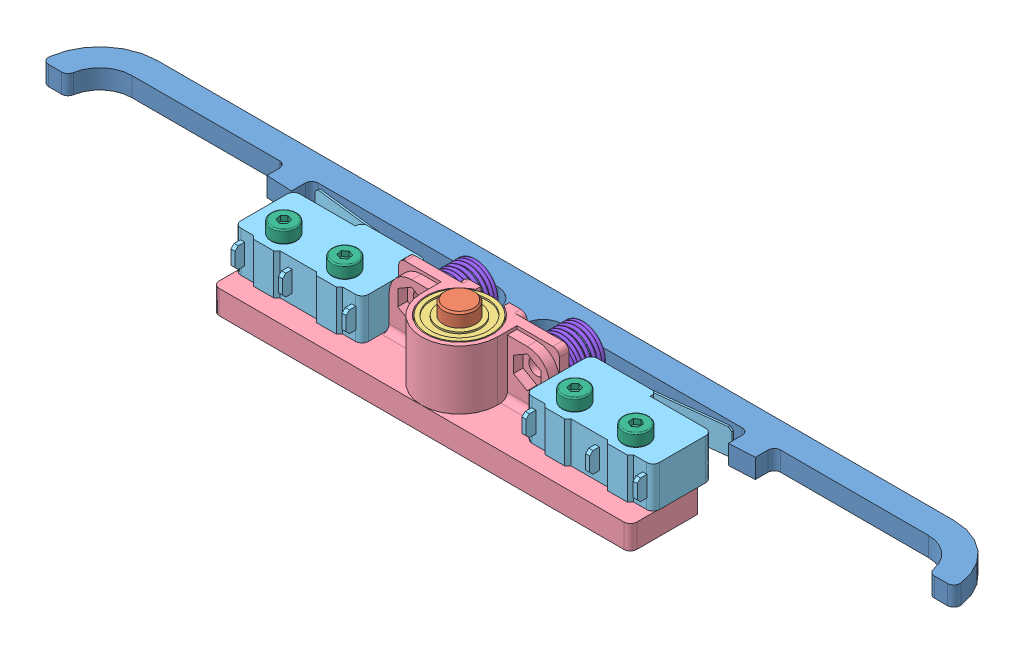
SolidWorks assembly bumper, configuration Default. Lengths in mm.
Overall size (141.87 14.98 21.84).
17 component instances, 8 part files, 45 mates.
Components (placement in the parent):
- bumper-body-1: bumper-body [Default] at (0 5.7 -13) size (141.87 3 19.5)
- bumper-pin-1: bumper-pin [Default] at (0 -1.5 0) x (0.989126 0 0.147073) z (-0.147073 0 0.989126) size (4.98 14.98 4.98)
- bearing-5x10x4-1: bearing-5x10x4 [Default] at (0 7.4 0) x (0.98772 0 -0.156233) z (0.156233 0 0.98772) size (10 4 10)
- bearing-5x10x4-3: bearing-5x10x4 [Default] x (0.862962 0 -0.505269) z (0.505269 0 0.862962) size (10 4 10)
- bumper-mount-1: bumper-mount [Default] at origin size (65 12.9 11.45)
- bumper-switch-1: bumper-switch [Default] at (22.65 5.375 -2.4) size (19.85 6.35 14.2)
- cap-screw-m2-10mm-1: cap-screw-m2-10mm [Default] at (27.4 10.55 -0.05) x (0 -1 0) z (0.048273 0 0.998834) size (12 4 4)
- nut-m2-1: nut-m2 [Default] at (27.4 -1.5 -0.05) x (-0.866025 0 0.5) z (0 1 0) size (4.62 4 2)
- cap-screw-m2-10mm-2: cap-screw-m2-10mm [Default] at (17.9 10.55 -0.05) x (0 -1 0) z (0.235644 0 0.97184) size (12 4 4)
- nut-m2-2: nut-m2 [Default] at (17.9 -1.5 -0.05) x (-0.866025 0 0.5) z (0 1 0) size (4.62 4 2)
- bumper-switch-3: bumper-switch [Default] at (-22.65 5.375 -2.4) x (-1 0 0) z (0 0 1) size (19.85 6.35 14.2)
- cap-screw-m2-10mm-6: cap-screw-m2-10mm [Default] at (-27.4 10.55 -0.05) x (0 -1 0) z (0.942478 0 0.334268) size (12 4 4)
- cap-screw-m2-10mm-8: cap-screw-m2-10mm [Default] at (-17.9 10.55 -0.05) x (0 -1 0) z (0.942478 0 0.334268) size (12 4 4)
- nut-m2-6: nut-m2 [Default] at (-17.9 -1.5 -0.05) x (-0.866025 0 0.5) z (0 1 0) size (4.62 4 2)
- nut-m2-8: nut-m2 [Default] at (-27.4 -1.5 -0.05) x (-0.866025 0 0.5) z (0 1 0) size (4.62 4 2)
- bumper-spring-1: bumper-spring [Default] at (-8.365 5.7 -11) x (1 0 0) z (0 -1 0) size (7.25 5.46 7.25)
- bumper-spring-2: bumper-spring [Default] at (8.365 5.7 -11) x (0.987351 0.158553 0) z (0.158553 -0.987351 0) size (7.25 5.46 7.25)
Mates (geometry in assembly coordinates):
- Concentric1: concentric: cylinder of bumper-body-1 through (0 7.2 0) axis (0 -1 0) radius 2.5; cylinder of bumper-pin-1 through (0 13.48 0) axis (0 -1 0) radius 2.49
- Concentric2: concentric: cylinder of bumper-pin-1 through (0 13.48 0) axis (0 -1 0) radius 2.49; cylinder of bearing-5x10x4-1 through (0 11.4 0) axis (0 -1 0) radius 2.5
- Concentric4: concentric: cylinder of bumper-pin-1 through (0 13.48 0) axis (0 -1 0) radius 2.49; cylinder of bearing-5x10x4-3 through (0 4 0) axis (0 -1 0) radius 2.5
- Concentric7: concentric: cylinder of bumper-pin-1 through (0 13.88 0) axis (0 -1 0) radius 2.49; cylinder of ? through (0 10 0) axis (0 -1 0) radius 2.525
- Coincident3: coincident: plane of bumper-body-1 through (-0.0163 8.5 -12) normal (0 1 0); plane of ? through (0 8.5 0) normal (0 -1 0)
- Coincident4: coincident: plane of bearing-5x10x4-1 through (0 10 0) normal (0 -1 0); plane of ? through (0 10 0) normal (0 1 0)
- Concentric8: concentric: cylinder of bumper-pin-1 through (0 13.88 0) axis (0 -1 0) radius 2.49; cylinder of ? through (0 4 0) axis (0 1 0) radius 2.525
- Coincident5: coincident: plane of bumper-body-1 through (-0.0163 5.5 -12) normal (0 -1 0); plane of ? through (0 5.5 0) normal (0 1 0)
- Coincident6: coincident: plane of bearing-5x10x4-3 through (0 4 0) normal (0 1 0); plane of ? through (0 4 0) normal (0 -1 0)
- Coincident8: coincident: plane of bearing-5x10x4-3 through (0 0 0) normal (0 -1 0); plane of bumper-mount-1 through (0 0 0) normal (0 1 0)
- Concentric10: concentric: cylinder of bearing-5x10x4-3 through (0 4 0) axis (0 -1 0) radius 5; cylinder of bumper-mount-1 through (0 11.4 0) axis (0 -1 0) radius 5.2
- Distance1: distance = 0.2 mm: plane of bumper-body-1 through (0 4.2 -13) normal (0 -1 0); plane of bearing-5x10x4-3 through (0 4 0) normal (0 1 0)
- Distance2: distance = 0.2 mm: plane of bumper-body-1 through (0 7.2 -13) normal (0 1 0); plane of bearing-5x10x4-1 through (0 7.4 0) normal (0 -1 0)
- Coincident13: coincident: plane of bumper-pin-1 through (0 -1.5 0) normal (0 -1 0); plane of bumper-mount-1 through (0 -1.5 0) normal (0 -1 0)
- Parallel1: parallel: plane of bumper-body-1 through (0 7.2 -15) normal (0 0 -1); plane of bumper-mount-1 through (0 11.4 -4.55) normal (0 0 -1)
- Concentric11: concentric: line of bumper-mount-1 through (17.9 2.2 -0.05) axis (0 1 0); cylinder of bumper-switch-1 through (17.9 8.55 -0.05) axis (0 -1 0) radius 1.25
- Concentric12: concentric: line of bumper-mount-1 through (27.4 2.2 -0.05) axis (0 1 0); cylinder of bumper-switch-1 through (27.4 8.55 -0.05) axis (0 -1 0) radius 1.25
- Coincident15: coincident: plane of bumper-mount-1 through (0 2.2 0) normal (0 1 0); plane of bumper-switch-1 through (22.65 2.2 -2.4) normal (0 -1 0)
- Concentric13: concentric: cylinder of bumper-switch-1 through (27.4 8.55 -0.05) axis (0 -1 0) radius 1.25; cylinder of cap-screw-m2-10mm-1 through (27.4 12.8318 -0.05) axis (0 1 0) radius 1
- Coincident16: coincident: plane of bumper-switch-1 through (22.65 8.55 -2.4) normal (0 1 0); plane of cap-screw-m2-10mm-1 through (28.3988 8.55 -0.0983) normal (0 -1 0)
- Concentric14: concentric: cylinder of cap-screw-m2-10mm-1 through (27.4 12.8318 -0.05) axis (0 1 0) radius 1; cylinder of nut-m2-1 through (27.4 0.5 -0.05) axis (0 -1 0) radius 1
- Coincident17: coincident: plane of bumper-mount-1 through (0 0.5 0) normal (0 -1 0); plane of nut-m2-1 through (27.4 0.5 -0.05) normal (0 1 0)
- Parallel2: parallel: plane of bumper-mount-1 through (25.25 0.5 0) normal (1 0 0); plane of nut-m2-1 through (25.4 0.5 -1.2047) normal (-1 0 0)
- Concentric15: concentric: cylinder of bumper-switch-1 through (17.9 8.55 -0.05) axis (0 -1 0) radius 1.25; cylinder of cap-screw-m2-10mm-2 through (17.9 12.8318 -0.05) axis (0 1 0) radius 1
- Coincident19: coincident: plane of bumper-switch-1 through (22.65 8.55 -2.4) normal (0 1 0); plane of cap-screw-m2-10mm-2 through (18.8718 8.55 -0.2856) normal (0 -1 0)
- Concentric16: concentric: cylinder of cap-screw-m2-10mm-2 through (17.9 12.8318 -0.05) axis (0 1 0) radius 1; cylinder of nut-m2-2 through (17.9 0.5 -0.05) axis (0 -1 0) radius 1
- Coincident21: coincident: plane of bumper-mount-1 through (0 0.5 0) normal (0 -1 0); plane of nut-m2-2 through (17.9 0.5 -0.05) normal (0 1 0)
- Parallel3: parallel: plane of bumper-mount-1 through (15.75 0.5 0) normal (1 0 0); plane of nut-m2-2 through (15.9 0.5 -1.2047) normal (-1 0 0)
- Concentric21: concentric: line of bumper-mount-1 through (-27.4 2.2 -0.05) axis (0 1 0); cylinder of bumper-switch-3 through (-27.4 2.2 -0.05) axis (0 1 0) radius 1.25
- Concentric22: concentric: line of bumper-mount-1 through (-17.9 2.2 -0.05) axis (0 1 0); cylinder of bumper-switch-3 through (-17.9 2.2 -0.05) axis (0 1 0) radius 1.25
- Coincident25: coincident: plane of bumper-mount-1 through (0 2.2 0) normal (0 1 0); plane of bumper-switch-3 through (-22.65 2.2 -2.4) normal (0 -1 0)
- Concentric23: concentric: cylinder of bumper-switch-3 through (-27.4 2.2 -0.05) axis (0 1 0) radius 1.25; cylinder of cap-screw-m2-10mm-6 through (-27.4 12.8318 -0.05) axis (0 1 0) radius 1
- Coincident26: coincident: plane of bumper-switch-3 through (-22.65 8.55 -2.4) normal (0 1 0); plane of cap-screw-m2-10mm-6 through (-27.0657 8.55 -0.9925) normal (0 -1 0)
- Concentric24: concentric: cylinder of bumper-switch-3 through (-17.9 2.2 -0.05) axis (0 1 0) radius 1.25; cylinder of cap-screw-m2-10mm-8 through (-17.9 12.8318 -0.05) axis (0 1 0) radius 1
- Coincident27: coincident: plane of bumper-switch-3 through (-22.65 8.55 -2.4) normal (0 1 0); plane of cap-screw-m2-10mm-8 through (-17.5657 8.55 -0.9925) normal (0 -1 0)
- Concentric25: concentric: cylinder of cap-screw-m2-10mm-8 through (-17.9 12.8318 -0.05) axis (0 1 0) radius 1; cylinder of nut-m2-6 through (-17.9 0.5 -0.05) axis (0 -1 0) radius 1
- Coincident28: coincident: plane of bumper-mount-1 through (0 0.5 0) normal (0 -1 0); plane of nut-m2-6 through (-17.9 0.5 -0.05) normal (0 1 0)
- Parallel4: parallel: plane of bumper-mount-1 through (-20.05 0.5 0) normal (1 0 0); plane of nut-m2-6 through (-19.9 0.5 -1.2047) normal (-1 0 0)
- Concentric26: concentric: cylinder of cap-screw-m2-10mm-6 through (-27.4 12.8318 -0.05) axis (0 1 0) radius 1; cylinder of nut-m2-8 through (-27.4 0.5 -0.05) axis (0 -1 0) radius 1
- Coincident29: coincident: plane of bumper-mount-1 through (0 0.5 0) normal (0 -1 0); plane of nut-m2-8 through (-27.4 0.5 -0.05) normal (0 1 0)
- Parallel5: parallel: plane of bumper-mount-1 through (-29.55 0.5 0) normal (1 0 0); plane of nut-m2-8 through (-29.4 0.5 -1.2047) normal (-1 0 0)
- Coincident30: coincident: line of bumper-body-1 through (-8.365 5.7 -15) axis (0 0 1); line of bumper-spring-1 through (-8.365 5.7 -6.3393) axis (0 0 -1)
- Coincident31: coincident: plane of bumper-body-1 through (0 7.2 -11) normal (0 0 1); plane of bumper-spring-1 through (-8.365 5.7 -11) normal (0 0 1)
- Coincident32: coincident: line of bumper-body-1 through (8.365 5.7 -15) axis (0 0 1); line of bumper-spring-2 through (8.365 5.7 -6.3393) axis (0 0 -1)
- Coincident33: coincident: plane of bumper-body-1 through (0 7.2 -11) normal (0 0 1); plane of bumper-spring-2 through (8.365 5.7 -11) normal (0 0 1)
